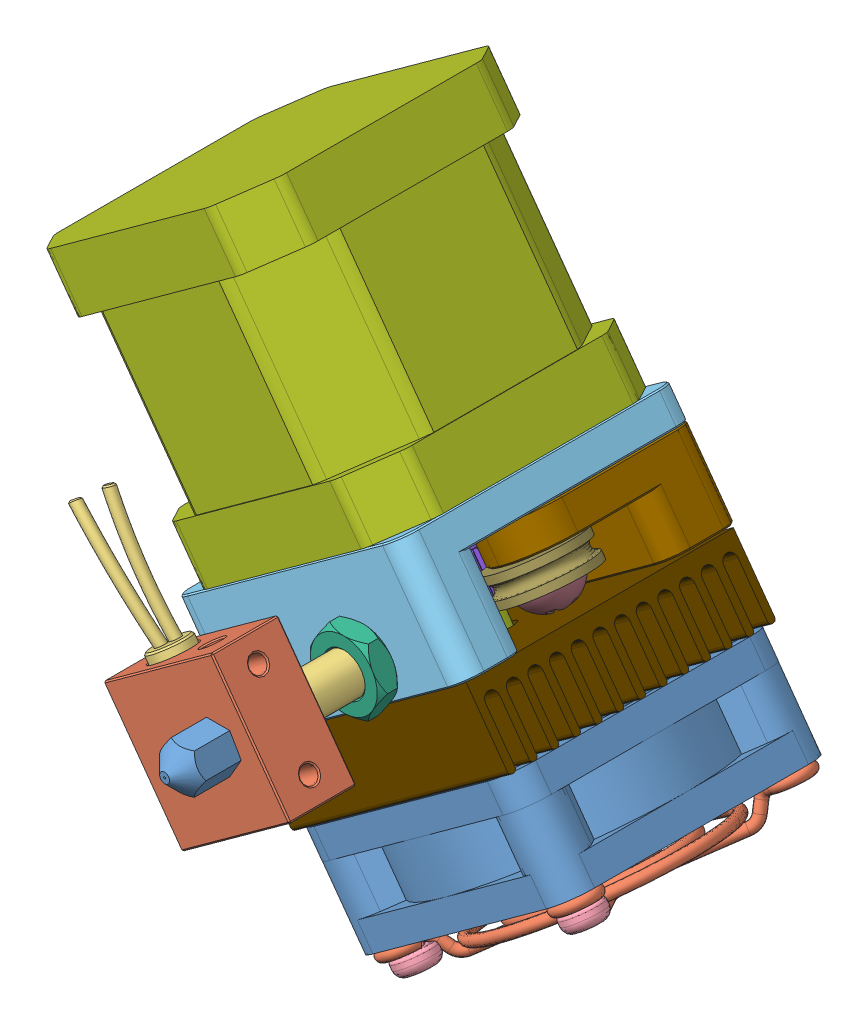
SolidWorks assembly Extruder, configuration По умолчанию. Lengths in mm.
Overall size (84.14 94.75 81.74).
23 component instances, 22 part files, 49 mates.
Components (placement in the parent):
- nozzle-1: nozzle [По умолчанию] at (3.4742 8.0512 4.4914) size (7.62 6 13)
- heater_block-1: heater_block [По умолчанию] at (-1.9939 -8.2614 -0.5086) x (0.809726 0.586808 0) z (0 0 1) size (20 20 10)
- thermal_barrier-1: thermal_barrier [По умолчанию] at (3.4742 8.0512 -25.5086) x (0.579859 -0.814717 0) z (0 0 1) size (6 6 30)
- caprolon-1: caprolon [По умолчанию] at (3.4742 8.0512 -15.5086) size (4 4 20)
- motor_bracket-1: motor_bracket [По умолчанию] at (8.5783 26.57 -12.3086) x (-0.809726 -0.586808 0) z (0.586808 -0.809726 0) size (42 42 17)
- nut_m5-1: nut_m5 [По умолчанию] at (3.4742 8.0512 -12.3086) size (12.7 10 3)
- 42HS40 Stepper Motor-1: 42HS40 Stepper Motor [По умолчанию] at (-13.1204 20.7248 -33.3086) x (0.809726 0.586808 0) z (0.586808 -0.809726 0) size (42 42 60.5)
- gear-1: gear [По умолчанию] at (0.0828 2.506 -33.3086) x (0.508265 0.36834 -0.778455) z (-0.586808 0.809726 0) size (10.99 10.98 11)
- clip-1: clip [По умолчанию] at (11.4663 22.982 -27.3695) x (-0.809678 -0.586774 0.010851) z (0.586808 -0.809726 0) size (52 27 12)
- bush-1: bush [По умолчанию] at (6.8242 19.6178 -48.8086) x (0.62411 0.452293 0.637117) z (0.586808 -0.809726 0) size (8 8 12)
- washer-1: washer [По умолчанию] at (7.1676 14.3093 -33.7769) x (0.737077 0.53416 0.413993) z (0.586808 -0.809726 0) size (8 8 0.5)
- special_bearing-1: special_bearing [По умолчанию] at (9.8082 10.6655 -33.7769) x (-0.586808 0.809726 0) z (0.000367 0.000266 1) size (4 13 13)
- screw-1: screw [По умолчанию] at (11.5686 8.2363 -33.7769) x (0.737077 0.53416 -0.413993) z (-0.586808 0.809726 0) size (8.61 8.61 10.93)
- m4x20-1: m4x20 [По умолчанию] at (-11.2125 -0.8633 -60.0204) x (-0.248557 -0.968581 0.008352) z (-0.008787 -0.006368 -0.999941) size (6.7 6.7 24.17)
- m5x8-1: m5x8 [По умолчанию] at (-11.0192 -0.7232 -38.0217) x (0.919178 0.3937 -0.010584) z (-0.008787 -0.006368 -0.999941) size (8 8 13.23)
- spring-1: spring [По умолчанию] at (-10.8777 -0.6206 -21.9226) x (0.999961 0.000006 -0.008787) z (0.008787 0.006368 0.999941) size (7.61 7.67 16.58)
- m3x10__-1: m3x10__ [Default] at (-11.4648 -0.3051 -23.8086) x (-0.947538 -0.319642 0) z (0.319642 -0.947538 0) size (4.7 12.07 4.7)
- heatsink-1: heatsink [По умолчанию] at (-14.6447 -11.2545 -53.3086) x (0 0 1) z (0.809726 0.586808 0) size (40 11 40)
- fan40х40-1: fan40х40 [Default] at (10.3419 -11.6715 -33.2961) x (0.809726 0.586808 0) z (-0.586808 0.809726 0) size (40.02 40.02 15)
- Fan grill 40 мм-1: Fan grill 40 мм [По умолчанию] at (18.2051 -22.5218 -33.3086) x (-0.809726 -0.586808 0) z (0 0 1) size (38.6 4.8 38.6)
- Heating Element-1: Heating Element [Default] at (-2.7226 4.3322 4.4914) x (0.586808 -0.809726 0) z (0.500422 0.362656 -0.786167) size (39.33 5.8 6.45)
- m3x54-1: m3x54 [По умолчанию] at (-24.1454 9.524 -17.8086) x (-0.809726 -0.586808 0) z (0 0 1) size (5.8 52.4 5.8)
- m3x54-2: m3x54 [По умолчанию] at (0.9561 27.7151 -17.8086) x (-0.809726 -0.586808 0) z (0 0 1) size (5.8 52.4 5.8)
Mates (geometry in assembly coordinates):
- Концентричный1: concentric anti-aligned: cylinder of nozzle-1 through (3.4742 8.0512 8.4914) axis (0 0 -1) radius 2.9; cylinder of heater_block-1 through (3.4742 8.0512 -0.5086) axis (0 0 1) radius 2.5
- Совпадение1: coincident anti-aligned: plane of nozzle-1 through (3.4742 8.0512 9.4914) normal (0 0 -1); plane of heater_block-1 through (-1.9939 -8.2614 9.4914) normal (0 0 1)
- Концентричный2: concentric anti-aligned: cylinder of thermal_barrier-1 through (3.4742 8.0512 -15.5086) axis (0 0 1) radius 2; cylinder of caprolon-1 through (3.4742 8.0512 4.4914) axis (0 0 -1) radius 2
- Совпадение2: coincident aligned: plane of thermal_barrier-1 through (3.4742 8.0512 4.4914) normal (0 0 1); plane of caprolon-1 through (3.4742 8.0512 4.4914) normal (0 0 1)
- Концентричный3: concentric anti-aligned: cylinder of heater_block-1 through (3.4742 8.0512 -0.5086) axis (0 0 1) radius 2.5; cylinder of thermal_barrier-1 through (3.4742 8.0512 4.4914) axis (0 0 -1) radius 3
- Совпадение3: coincident anti-aligned: plane of nozzle-1 through (3.4742 8.0512 4.4914) normal (0 0 -1); plane of thermal_barrier-1 through (3.4742 8.0512 4.4914) normal (0 0 1)
- Концентричный4: concentric aligned: cylinder of thermal_barrier-1 through (3.4742 8.0512 4.4914) axis (0 0 -1) radius 3; cylinder of motor_bracket-1 through (3.4742 8.0512 -9.4086) axis (0 0 -1) radius 2.5
- Параллельность1: parallel aligned: plane of heater_block-1 through (-13.7301 7.9331 9.4914) normal (-0.586808 0.809726 0); plane of motor_bracket-1 through (8.5783 26.57 -12.3086) normal (-0.586808 0.809726 0)
- Расстояние1: distance = 3.7 mm aligned: plane of motor_bracket-1 through (11.2777 22.8453 -21.8086) normal (0 0 -1); plane of thermal_barrier-1 through (3.4742 8.0512 -25.5086) normal (0 0 -1)
- Концентричный5: concentric aligned: cylinder of thermal_barrier-1 through (3.4742 8.0512 4.4914) axis (0 0 -1) radius 3; cylinder of nut_m5-1 through (3.4742 8.0512 -9.3086) axis (0 0 -1) radius 3
- Совпадение6: coincident anti-aligned: plane of motor_bracket-1 through (18.5541 12.8047 -12.3086) normal (0 0 1); plane of nut_m5-1 through (3.4742 8.0512 -12.3086) normal (0 0 -1)
- Совпадение7: coincident anti-aligned: plane of motor_bracket-1 through (8.5783 26.57 -12.3086) normal (-0.586808 0.809726 0); plane of 42HS40 Stepper Motor-1 through (8.5783 26.57 -54.3086) normal (0.586808 -0.809726 0)
- Концентричный6: concentric aligned: cylinder of motor_bracket-1 through (-1.1495 4.2064 -33.3086) axis (-0.586808 0.809726 0) radius 11.05; cylinder of 42HS40 Stepper Motor-1 through (-7.5457 13.0325 -33.3086) axis (-0.586808 0.809726 0) radius 11
- Параллельность2: parallel aligned: plane of motor_bracket-1 through (18.5541 12.8047 -12.3086) normal (0.809726 0.586808 0); plane of 42HS40 Stepper Motor-1 through (8.5783 26.57 -12.3086) normal (0.809726 0.586808 0)
- Концентричный10: concentric anti-aligned: cylinder of 42HS40 Stepper Motor-1 through (3.6037 -2.3523 -33.3086) axis (-0.586808 0.809726 0) radius 2.5; cylinder of gear-1 through (-6.3721 11.413 -33.3086) axis (0.586808 -0.809726 0) radius 2.5
- Концентричный11: concentric anti-aligned: cylinder of motor_bracket-1 through (19.3819 2.2897 -48.8086) axis (-0.586808 0.809726 0) radius 1.75; cylinder of clip-1 through (6.8242 19.6178 -48.8086) axis (0.586808 -0.809726 0) radius 3.3
- Совпадение13: coincident anti-aligned: plane of motor_bracket-1 through (11.2777 22.8453 -12.3086) normal (0.586808 -0.809726 0); plane of clip-1 through (11.4663 22.982 -27.3695) normal (-0.586808 0.809726 0)
- Концентричный12: concentric anti-aligned: cylinder of clip-1 through (6.8242 19.6178 -48.8086) axis (0.586808 -0.809726 0) radius 3.3; cylinder of bush-1 through (13.3964 10.5489 -48.8086) axis (-0.586808 0.809726 0) radius 3.2
- Совпадение14: coincident anti-aligned: plane of motor_bracket-1 through (11.2777 22.8453 -12.3086) normal (0.586808 -0.809726 0); plane of bush-1 through (6.8242 19.6178 -48.8086) normal (-0.586808 0.809726 0)
- Совпадение15: coincident anti-aligned: plane of clip-1 through (14.107 19.3382 -27.3695) normal (0.586808 -0.809726 0); plane of washer-1 through (7.1676 14.3093 -33.7769) normal (-0.586808 0.809726 0)
- Концентричный13: concentric anti-aligned: cylinder of clip-1 through (3.0599 19.9773 -33.7769) axis (0.586808 -0.809726 0) radius 1.6; cylinder of washer-1 through (7.461 13.9044 -33.7769) axis (-0.586808 0.809726 0) radius 2
- Совпадение16: coincident anti-aligned: plane of washer-1 through (7.461 13.9044 -33.7769) normal (0.586808 -0.809726 0); plane of special_bearing-1 through (5.8415 12.7308 -33.776) normal (-0.586808 0.809726 0)
- Концентричный14: concentric anti-aligned: cylinder of clip-1 through (3.0599 19.9773 -33.7769) axis (0.586808 -0.809726 0) radius 1.6; cylinder of special_bearing-1 through (5.5901 16.4859 -33.7769) axis (-0.586808 0.809726 0) radius 2
- Концентричный15: concentric anti-aligned: cylinder of special_bearing-1 through (5.5901 16.4859 -33.7769) axis (-0.586808 0.809726 0) radius 2; cylinder of screw-1 through (5.1137 17.1433 -33.7769) axis (0.586808 -0.809726 0) radius 2
- Совпадение17: coincident anti-aligned: plane of special_bearing-1 through (8.1888 9.4919 -33.776) normal (0.586808 -0.809726 0); plane of screw-1 through (9.8082 10.6655 -33.7769) normal (-0.586808 0.809726 0)
- Расстояние5: distance = 6 mm aligned: plane of 42HS40 Stepper Motor-1 through (3.6037 -2.3523 -33.3086) normal (0.586808 -0.809726 0); plane of gear-1 through (0.0828 2.506 -33.3086) normal (0.586808 -0.809726 0)
- Концентричный16: concentric aligned: cylinder of clip-1 through (-11.0306 -0.7314 -39.3216) axis (-0.008787 -0.006368 -0.999941) radius 1.6; cylinder of m4x20-1 through (-11.0368 -0.7359 -40.0215) axis (-0.008787 -0.006368 -0.999941) radius 2
- Расстояние6: distance = 3 mm aligned: plane of m4x20-1 through (-11.0368 -0.7359 -40.0215) normal (0.008787 0.006368 0.999941); plane of clip-1 through (13.9664 19.2363 -43.3686) normal (0.008787 0.006368 0.999941)
- Концентричный17: concentric anti-aligned: cylinder of m4x20-1 through (-11.0368 -0.7359 -40.0215) axis (-0.008787 -0.006368 -0.999941) radius 2; cylinder of m5x8-1 through (-11.0631 -0.755 -43.0214) axis (0.008787 0.006368 0.999941) radius 4
- Совпадение20: coincident anti-aligned: plane of clip-1 through (13.9664 19.2363 -43.3686) normal (0.008787 0.006368 0.999941); plane of m5x8-1 through (-11.0631 -0.755 -43.0214) normal (-0.008787 -0.006368 -0.999941)
- Совпадение21: coincident anti-aligned: plane of m5x8-1 through (-11.0192 -0.7232 -38.0217) normal (0.008787 0.006368 0.999941); plane of spring-1 through (-6.8958 16.2765 -38.1661) normal (-0.008787 -0.006368 -0.999941)
- Концентричный18: concentric aligned: cylinder of m5x8-1 through (-10.9489 -0.6722 -30.0221) axis (-0.008787 -0.006368 -0.999941) radius 2.5; cylinder of spring-1 through (-10.7283 -0.5124 -4.9236) axis (-0.008787 -0.006368 -0.999941) radius 3.2
- Концентричный19: concentric anti-aligned: cylinder of motor_bracket-1 through (-11.4648 -0.3051 -9.4086) axis (0 0 -1) radius 1.25; cylinder of m3x10__-1 through (-11.4648 -0.3051 2.5414) axis (0 0 1) radius 1.5
- Расстояние7: distance = 2 mm anti-aligned: plane of motor_bracket-1 through (11.2777 22.8453 -21.8086) normal (0 0 -1); plane of m3x10__-1 through (-11.9443 1.1162 -23.8086) normal (0 0 1)
- Совпадение24: coincident anti-aligned: plane of motor_bracket-1 through (18.5541 12.8047 -12.3086) normal (0.586808 -0.809726 0); plane of heatsink-1 through (17.7444 12.2179 -53.3086) normal (-0.586808 0.809726 0)
- Расстояние8: distance = 1 mm aligned: plane of heatsink-1 through (17.7444 12.2179 -53.3086) normal (0.809726 0.586808 0); plane of motor_bracket-1 through (18.5541 12.8047 -12.3086) normal (0.809726 0.586808 0)
- Расстояние9: distance = 1 mm aligned: plane of heatsink-1 through (17.7444 12.2179 -53.3086) normal (0 0 -1); plane of motor_bracket-1 through (18.5541 12.8047 -54.3086) normal (0 0 -1)
- Совпадение27: coincident anti-aligned: plane of heatsink-1 through (24.1993 3.3109 -53.3086) normal (0.586808 -0.809726 0); plane of fan40х40-1 through (7.9946 -8.4326 -33.2961) normal (-0.586808 0.809726 0)
- Совпадение28: coincident aligned: plane of heatsink-1 through (17.7444 12.2179 -53.3086) normal (0.809726 0.586808 0); plane of fan40х40-1 through (24.1993 3.3109 -33.2961) normal (0.809726 0.586808 0)
- Совпадение29: coincident aligned: plane of heatsink-1 through (17.7444 12.2179 -53.3086) normal (0 0 -1); plane of fan40х40-1 through (7.9946 -8.4326 -53.3086) normal (0 0 -1)
- Совпадение31: coincident aligned: plane of fan40х40-1 through (29.7524 -11.1896 -17.2961) normal (0.586808 -0.809726 0); plane of Fan grill 40 мм-1
- Расстояние10: distance = 20 mm anti-aligned: plane of Fan grill 40 мм-1; plane of fan40х40-1 through (32.9913 -8.8423 -49.2961) normal (0.809726 0.586808 0)
- Расстояние11: distance = 20 mm anti-aligned: plane of Fan grill 40 мм-1 through (18.2051 -22.5218 -33.3086) normal (0 0 1); plane of fan40х40-1 through (7.9946 -8.4326 -53.3086) normal (0 0 -1)
- Концентричный22: concentric anti-aligned: cylinder of heater_block-1 through (-8.2239 11.9234 4.4914) axis (0.586808 -0.809726 0) radius 3; cylinder of Heating Element-1 through (3.5122 -4.2711 4.4914) axis (-0.586808 0.809726 0) radius 2.9
- Совпадение34: coincident aligned: plane of heater_block-1 through (-1.9939 -8.2614 9.4914) normal (0.586808 -0.809726 0); plane of Heating Element-1 through (3.5122 -4.2711 4.4914) normal (0.586808 -0.809726 0)
- Концентричный23: concentric anti-aligned: cylinder of 42HS40 Stepper Motor-1 through (-20.9766 5.1515 -17.8086) axis (0.586808 -0.809726 0) radius 1.25; cylinder of m3x54-1 through (-24.1454 9.524 -17.8086) axis (-0.586808 0.809726 0) radius 1.5
- Расстояние12: distance = 1.6 mm anti-aligned: plane of m3x54-1 through (2.8468 -32.664 -17.8086) normal (-0.586808 0.809726 0); plane of fan40х40-1 through (29.7524 -11.1896 -17.2961) normal (0.586808 -0.809726 0)
- Концентричный24: concentric anti-aligned: cylinder of 42HS40 Stepper Motor-1 through (4.1249 23.3426 -17.8086) axis (0.586808 -0.809726 0) radius 1.25; cylinder of m3x54-2 through (0.9561 27.7151 -17.8086) axis (-0.586808 0.809726 0) radius 1.5
- Расстояние13: distance = 1.6 mm anti-aligned: plane of fan40х40-1 through (29.7524 -11.1896 -17.2961) normal (0.586808 -0.809726 0); plane of m3x54-2 through (27.9483 -14.4729 -17.8086) normal (-0.586808 0.809726 0)
